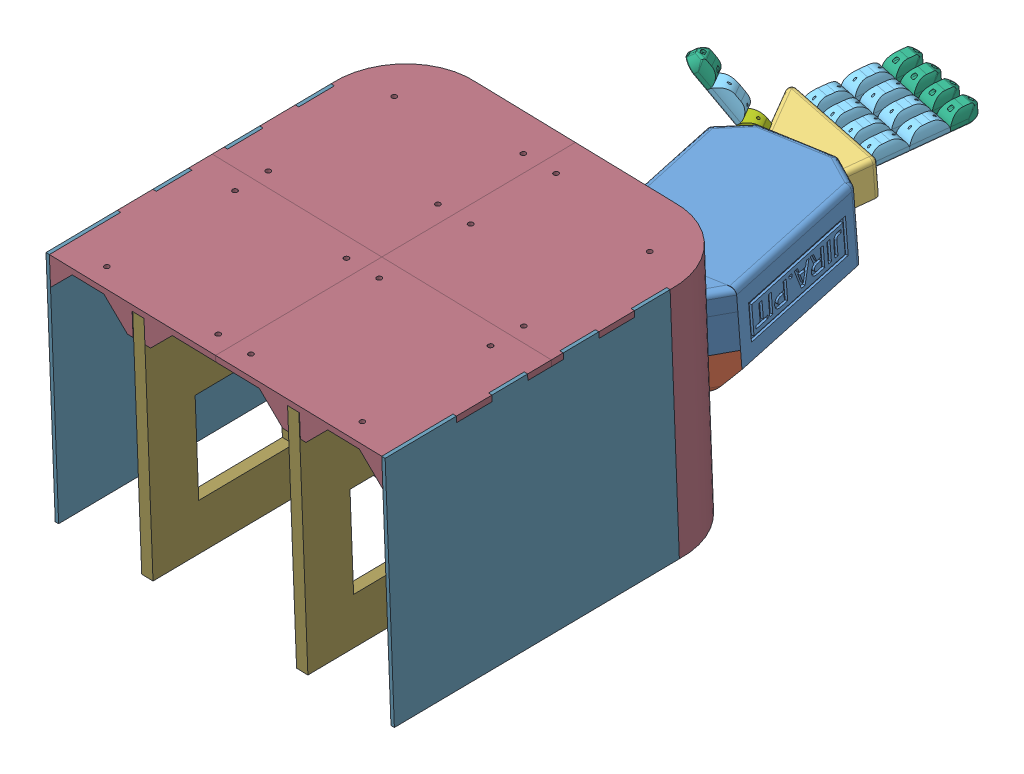
SolidWorks assembly Assem, configuration Default. Lengths in mm.
Overall size (307.81 220.18 663.52).
29 component instances, 15 part files, 77 mates.
Components (placement in the parent):
- LowerArm-1: LowerArm [Default] at (-155.348 -1.3022 43.2847) x (-0.988027 -0.013839 0.153662) z (0.154272 -0.076158 0.985089) size (110 63 197.6)
- LowerArmJoint-1: LowerArmJoint [Default] at (-124.2195 -72.1225 181.1445) x (0.154272 -0.076158 0.985089) z (0.988027 0.013839 -0.153662) size (64.86 30 110)
- Palm-1: Palm [Default] at (-140.1388 -9.6881 -22.7507) x (-0.988027 -0.013839 0.153662) z (0.154272 -0.076158 0.985089) size (87.73 30 62.31)
- UpperArm-1: UpperArm [Default] at (-132.8487 -39.1925 297.2691) x (-0.024858 -0.077406 0.99669) z (0.999689 0 0.024933) size (144 70 85.19)
- Finger-1: Finger [Default] at (-170.0006 -16.6103 30.209) x (0.981205 -0.013043 0.192525) z (-0.192957 -0.076299 0.978236) size (15.02 13 30)
- FingerTip-1: FingerTip [Default] at (-157.8446 -11.8036 -31.4185) x (0.981205 -0.013043 0.192525) z (-0.192957 -0.076299 0.978236) size (15.05 13 24.05)
- Finger-2: Finger [Default] at (-164.2119 -14.3213 0.8619) x (0.981205 -0.013043 0.192525) z (-0.192957 -0.076299 0.978236) size (15.02 13 30)
- Finger-3: Finger [Default] at (-183.836 -14.0604 -2.9886) x (0.981205 -0.013043 0.192525) z (-0.192957 -0.076299 0.978236) size (15.02 13 30)
- FingerTip-2: FingerTip [Default] at (-177.4687 -11.5427 -35.269) x (0.981205 -0.013043 0.192525) z (-0.192957 -0.076299 0.978236) size (15.05 13 24.05)
- Finger-4: Finger [Default] at (-189.6247 -16.3494 26.3585) x (0.981205 -0.013043 0.192525) z (-0.192957 -0.076299 0.978236) size (15.02 13 30)
- Finger-5: Finger [Default] at (-228.8729 -15.8277 18.6575) x (0.981205 -0.013043 0.192525) z (-0.192957 -0.076299 0.978236) size (15.02 13 30)
- FingerTip-3: FingerTip [Default] at (-216.7169 -11.021 -42.97) x (0.981205 -0.013043 0.192525) z (-0.192957 -0.076299 0.978236) size (15.05 13 24.05)
- Finger-6: Finger [Default] at (-223.0842 -13.5387 -10.6896) x (0.981205 -0.013043 0.192525) z (-0.192957 -0.076299 0.978236) size (15.02 13 30)
- Finger-7: Finger [Default] at (-203.4601 -13.7996 -6.8391) x (0.981205 -0.013043 0.192525) z (-0.192957 -0.076299 0.978236) size (15.02 13 30)
- FingerTip-4: FingerTip [Default] at (-197.0928 -11.2818 -39.1195) x (0.981205 -0.013043 0.192525) z (-0.192957 -0.076299 0.978236) size (15.05 13 24.05)
- Finger-8: Finger [Default] at (-209.2488 -16.0885 22.508) x (0.981205 -0.013043 0.192525) z (-0.192957 -0.076299 0.978236) size (15.02 13 30)
- ThumbBase-1: ThumbBase [Default] at (-217.1763 -20.4802 47.8342) x (-0.482893 0.066832 -0.873125) z (0.503849 -0.794295 -0.339458) size (15.31 18.85 30.98)
- Finger-10: Finger [Default] at (-201.1767 -20.6009 38.9761) x (-0.482893 0.066832 -0.873125) z (0.503849 -0.794295 -0.339458) size (15.02 13 30)
- FingerTip-5: FingerTip [Default] at (-217.803 5.6097 50.1778) x (-0.482893 0.066832 -0.873125) z (0.503849 -0.794295 -0.339458) size (15.05 13 24.05)
- ArmGear-1: ArmGear [Default] at (-110.8327 -50.9907 296.9019) x (0.024858 0.077406 -0.99669) z (0.999689 0 0.024933) size (81.99 81.94 8)
- ServoGear-1: ServoGear [Default] at (-112.4171 -43.3937 360.4297) x (0.023749 0.304466 -0.952227) z (0.999689 0 0.024933) size (49.97 49.91 8)
- ArmShaft-1: ArmShaft [Default] at (-207.8026 -50.9907 294.4835) x (0.005579 -0.974646 -0.223685) z (0.999689 0 0.024933) size (8 8 127)
- ServoShaft-1: ServoShaft [Default] at (-225.9021 -43.3937 357.5993) x (0.019414 -0.627466 -0.778402) z (0.999689 0 0.024933) size (3.8 3.8 160)
- GearWall-1: GearWall [Default] at (-73.9011 14.411 420.4279) x (-0.999689 0 -0.024933) z (-0.024915 -0.0379 0.998971) size (10 200 300)
- GearWall-2: GearWall [Default] at (-210.8585 14.411 417.0122) x (-0.999689 0 -0.024933) z (-0.024915 -0.0379 0.998971) size (10 200 300)
- Base-2: Base [Default] at (-147.4774 119.3355 422.5737) x (-0.024915 -0.0379 0.998971) z (0.999689 0 0.024933) size (303.08 205 300.16)
- SideWall-1: SideWall [Default] at (-1.1737 15.7721 452.3243) x (0.999689 0 0.024933) z (0.024915 0.0379 -0.998971) size (3 205 240)
- SideWall-2: SideWall [Default] at (-298.0814 15.7721 444.9194) x (0.999689 0 0.024933) z (0.024915 0.0379 -0.998971) size (3 205 240)
- FloatingRoof-1: FloatingRoof [Default] at (-145.1876 19.7448 330.7617) x (-0.024915 -0.0379 0.998971) z (-0.999689 0 -0.024933) size (135 3 127)
Mates (geometry in assembly coordinates):
- Coincident1: coincident aligned: plane of FingerTip-1 through (-139.2074 -24.9713 -49.3836) normal (0.00193 -0.997 -0.077382); plane of Finger-2 through (-144.9961 -27.2603 -20.0365) normal (0.00193 -0.997 -0.077382)
- Coincident2: coincident aligned: plane of Finger-1 through (-150.7848 -29.5492 9.3106) normal (0.00193 -0.997 -0.077382); plane of Finger-2 through (-144.9961 -27.2603 -20.0365) normal (0.00193 -0.997 -0.077382)
- Coincident3: coincident aligned: line of FingerTip-1 through (-137.554 -23.9165 -62.9328) axis (-0.192957 -0.076299 0.978236); line of Finger-2 through (-140.3815 -25.0346 -48.5979) axis (-0.192957 -0.076299 0.978236)
- Coincident6: coincident aligned: line of Finger-1 through (-146.1702 -27.3235 -19.2508) axis (-0.192957 -0.076299 0.978236); line of Finger-2 through (-140.3815 -25.0346 -48.5979) axis (-0.192957 -0.076299 0.978236)
- Concentric1: concentric anti-aligned: circle of LowerArm-1; circle of UpperArm-1
- Concentric2: concentric aligned: circle of LowerArm-1; circle of UpperArm-1
- Coincident8: coincident anti-aligned: plane of LowerArm-1 through (-155.3191 -16.2572 42.1239) normal (0.00193 -0.997 -0.077382); plane of UpperArm-1 through (-109.6281 -25.9683 168.3833) normal (-0.00193 0.997 0.077382)
- Coincident13: coincident anti-aligned: plane of LowerArm-1 through (-155.2322 -61.1222 38.6418) normal (-0.154272 0.076158 -0.985089); plane of Palm-1 through (-204.2363 -45.3577 47.5349) normal (0.154272 -0.076158 0.985089)
- Concentric5: concentric anti-aligned: cylinder of Finger-1 through (-152.3769 -15.8963 -20.6061) axis (-0.192957 -0.076299 0.978236) radius 0.75; cylinder of Palm-1 through (-158.7445 -18.4142 11.6757) axis (0.192957 0.076299 -0.978236) radius 0.75
- Concentric17: concentric anti-aligned: circle of LowerArm-1; circle of Palm-1
- Concentric22: concentric anti-aligned: circle of LowerArm-1; circle of Palm-1
- Concentric24: concentric anti-aligned: circle of Finger-1; circle of Palm-1
- Coincident27: coincident anti-aligned: plane of Finger-1 through (-150.7848 -29.5492 9.3106) normal (-0.192957 -0.076299 0.978236); plane of Palm-1 through (-139.4764 -42.3611 10.5419) normal (0.192957 0.076299 -0.978236)
- Coincident28: coincident anti-aligned: plane of Finger-1 through (-144.9961 -27.2603 -20.0365) normal (0.192957 0.076299 -0.978236); plane of Finger-2 through (-144.9961 -27.2603 -20.0365) normal (-0.192957 -0.076299 0.978236)
- Coincident29: coincident anti-aligned: plane of FingerTip-1 through (-139.2074 -24.9713 -49.3836) normal (-0.192957 -0.076299 0.978236); plane of Finger-2 through (-139.2074 -24.9713 -49.3836) normal (0.192957 0.076299 -0.978236)
- Coincident30: coincident aligned: line of Finger-3 through (-160.0056 -24.7737 -52.4484) axis (-0.192957 -0.076299 0.978236); line of Finger-4 through (-165.7943 -27.0626 -23.1013) axis (-0.192957 -0.076299 0.978236)
- Coincident31: coincident aligned: line of Finger-3 through (-160.0056 -24.7737 -52.4484) axis (-0.192957 -0.076299 0.978236); line of FingerTip-2 through (-157.1781 -23.6556 -66.7833) axis (-0.192957 -0.076299 0.978236)
- Coincident32: coincident aligned: plane of Finger-3 through (-164.6202 -26.9994 -23.887) normal (0.00193 -0.997 -0.077382); plane of FingerTip-2 through (-158.8315 -24.7104 -53.2341) normal (0.00193 -0.997 -0.077382)
- Coincident33: coincident aligned: plane of Finger-3 through (-164.6202 -26.9994 -23.887) normal (0.00193 -0.997 -0.077382); plane of Finger-4 through (-170.4089 -29.2884 5.4601) normal (0.00193 -0.997 -0.077382)
- Coincident34: coincident anti-aligned: plane of Finger-3 through (-158.8315 -24.7104 -53.2341) normal (0.192957 0.076299 -0.978236); plane of FingerTip-2 through (-158.8315 -24.7104 -53.2341) normal (-0.192957 -0.076299 0.978236)
- Coincident35: coincident anti-aligned: plane of Finger-3 through (-164.6202 -26.9994 -23.887) normal (-0.192957 -0.076299 0.978236); plane of Finger-4 through (-164.6202 -26.9994 -23.887) normal (0.192957 0.076299 -0.978236)
- Coincident36: coincident aligned: line of FingerTip-3 through (-196.4263 -23.1339 -74.4843) axis (-0.192957 -0.076299 0.978236); line of Finger-6 through (-199.2538 -24.252 -60.1494) axis (-0.192957 -0.076299 0.978236)
- Coincident37: coincident aligned: plane of Finger-5 through (-209.6571 -28.7666 -2.2409) normal (0.00193 -0.997 -0.077382); plane of Finger-6 through (-203.8684 -26.4777 -31.588) normal (0.00193 -0.997 -0.077382)
- Coincident38: coincident aligned: plane of FingerTip-3 through (-198.0797 -24.1887 -60.9351) normal (0.00193 -0.997 -0.077382); plane of Finger-6 through (-203.8684 -26.4777 -31.588) normal (0.00193 -0.997 -0.077382)
- Coincident39: coincident anti-aligned: plane of FingerTip-3 through (-198.0797 -24.1887 -60.9351) normal (-0.192957 -0.076299 0.978236); plane of Finger-6 through (-198.0797 -24.1887 -60.9351) normal (0.192957 0.076299 -0.978236)
- Coincident40: coincident anti-aligned: plane of Finger-5 through (-203.8684 -26.4777 -31.588) normal (0.192957 0.076299 -0.978236); plane of Finger-6 through (-203.8684 -26.4777 -31.588) normal (-0.192957 -0.076299 0.978236)
- Coincident41: coincident aligned: line of Finger-5 through (-205.0425 -26.5409 -30.8023) axis (-0.192957 -0.076299 0.978236); line of Finger-6 through (-199.2538 -24.252 -60.1494) axis (-0.192957 -0.076299 0.978236)
- Coincident42: coincident aligned: plane of Finger-7 through (-184.2443 -26.7385 -27.7375) normal (0.00193 -0.997 -0.077382); plane of FingerTip-4 through (-178.4556 -24.4496 -57.0846) normal (0.00193 -0.997 -0.077382)
- Coincident43: coincident aligned: plane of Finger-7 through (-184.2443 -26.7385 -27.7375) normal (0.00193 -0.997 -0.077382); plane of Finger-8 through (-190.033 -29.0275 1.6096) normal (0.00193 -0.997 -0.077382)
- Coincident44: coincident aligned: line of Finger-7 through (-179.6297 -24.5128 -56.2989) axis (-0.192957 -0.076299 0.978236); line of FingerTip-4 through (-176.8022 -23.3948 -70.6338) axis (-0.192957 -0.076299 0.978236)
- Coincident45: coincident aligned: line of Finger-7 through (-179.6297 -24.5128 -56.2989) axis (-0.192957 -0.076299 0.978236); line of Finger-8 through (-185.4184 -26.8018 -26.9518) axis (-0.192957 -0.076299 0.978236)
- Coincident46: coincident anti-aligned: plane of Finger-7 through (-184.2443 -26.7385 -27.7375) normal (-0.192957 -0.076299 0.978236); plane of Finger-8 through (-184.2443 -26.7385 -27.7375) normal (0.192957 0.076299 -0.978236)
- Coincident47: coincident anti-aligned: plane of Finger-7 through (-178.4556 -24.4496 -57.0846) normal (0.192957 0.076299 -0.978236); plane of FingerTip-4 through (-178.4556 -24.4496 -57.0846) normal (-0.192957 -0.076299 0.978236)
- Coincident48: coincident anti-aligned: circle of Palm-1; circle of Finger-4
- Concentric25: concentric anti-aligned: circle of Palm-1; cylinder of Finger-4 through (-172.001 -15.6355 -24.4566) axis (-0.192957 -0.076299 0.978236) radius 0.75
- Coincident51: coincident anti-aligned: circle of Palm-1; circle of Finger-8
- Concentric29: concentric anti-aligned: circle of Palm-1; cylinder of Finger-8 through (-191.6251 -15.3746 -28.3071) axis (-0.192957 -0.076299 0.978236) radius 0.75
- Concentric30: concentric anti-aligned: circle of Palm-1; cylinder of Finger-5 through (-211.2492 -15.1137 -32.1576) axis (-0.192957 -0.076299 0.978236) radius 0.75
- Coincident54: coincident anti-aligned: circle of Palm-1; circle of Finger-5
- Coincident55: coincident anti-aligned: plane of LowerArm-1 through (-133.6341 -71.7844 176.5542) normal (0.154272 -0.076158 0.985089); plane of LowerArmJoint-1 through (-125.1161 -86.6205 174.0732) normal (-0.154272 0.076158 -0.985089)
- Concentric35: concentric aligned: circle of LowerArmJoint-1; circle of UpperArm-1
- Coincident59: coincident anti-aligned: plane of Palm-1 through (-210.2546 -30.7376 31.5387) normal (-0.00193 0.997 0.077382); plane of ThumbBase-1 through (-210.3995 -30.7176 31.2768) normal (0.00193 -0.997 -0.077382)
- Coincident61: coincident anti-aligned: plane of Palm-1 through (-235.0693 -41.0904 -8.2147) normal (-0.875677 -0.039052 0.481315); plane of ThumbBase-1 through (-215.1928 -34.0235 28.5208) normal (0.875677 0.039052 -0.481315)
- Coincident62: coincident aligned: line of Palm-1 through (-211.3653 -30.5839 29.5305) axis (-0.875677 -0.039052 0.481315); line of ThumbBase-1 through (-211.3653 -30.5839 29.5305) axis (-0.875677 -0.039052 0.481315)
- Coincident69: coincident anti-aligned: line of ThumbBase-1 through (-225.7169 -9.9489 45.866) axis (0.482893 -0.066832 0.873125); line of Finger-10 through (-222.5556 -10.3865 51.5819) axis (-0.482893 0.066832 -0.873125)
- Coincident70: coincident anti-aligned: plane of ThumbBase-1 through (-230.4659 -9.9462 38.8108) normal (-0.503849 0.794295 0.339458); plane of Finger-10 through (-230.5153 -9.9878 38.8349) normal (0.503849 -0.794295 -0.339458)
- Coincident71: coincident anti-aligned: plane of Finger-10 through (-245.6307 13.841 49.0187) normal (-0.503849 0.794295 0.339458); plane of FingerTip-5 through (-245.6307 13.841 49.0187) normal (0.503849 -0.794295 -0.339458)
- Coincident72: coincident aligned: line of Finger-10 through (-243.4821 15.6526 47.969) axis (0.482893 -0.066832 0.873125); line of FingerTip-5 through (-243.4821 15.6526 47.969) axis (0.482893 -0.066832 0.873125)
- Coincident73: coincident aligned: line of Finger-10 through (-229.799 -9.384 38.485) axis (-0.503849 0.794295 0.339458); line of FingerTip-5 through (-244.9145 14.4449 48.6688) axis (-0.503849 0.794295 0.339458)
- Coincident75: coincident aligned: plane of ThumbBase-1 through (-223.673 -18.6735 34.3859) normal (-0.482893 0.066832 -0.873125); plane of Finger-10 through (-235.7613 0.0152 42.502) normal (-0.482893 0.066832 -0.873125)
- Coincident76: coincident anti-aligned: plane of LowerArm-1 through (-155.2612 -46.1672 39.8025) normal (0.00193 -0.997 -0.077382); plane of LowerArmJoint-1 through (-146.0522 -60.5273 225.0504) normal (-0.00193 0.997 0.077382)
- Coincident77: coincident anti-aligned: plane of UpperArm-1 through (-110.8327 -50.9907 296.9019) normal (0.999689 0 0.024933); plane of ArmGear-1 through (-110.8327 -50.9907 296.9019) normal (-0.999689 0 -0.024933)
- Concentric36: concentric aligned: circle of UpperArm-1; circle of ArmGear-1
- Parallel1: parallel aligned: plane of ArmGear-1 through (-102.8352 -50.9907 297.1014) normal (0.999689 0 0.024933); plane of ServoGear-1 through (-104.4196 -43.3937 360.6291) normal (0.999689 0 0.024933)
- Coincident79: coincident aligned: plane of ArmGear-1 through (-102.8352 -50.9907 297.1014) normal (0.999689 0 0.024933); plane of ServoGear-1 through (-104.4196 -43.3937 360.6291) normal (0.999689 0 0.024933)
- Concentric38: concentric anti-aligned: circle of ArmGear-1; circle of GearWall1-1
- Concentric40: concentric anti-aligned: circle of ServoGear-1; circle of GearWall1-1
- Parallel2: parallel aligned: line of UpperArm-1 through (-102.694 -57.699 291.4404) axis (0.00193 -0.997 -0.077382); line of ArmGear-1 through (-102.7223 -57.6601 292.573) axis (0.00193 -0.997 -0.077382)
- Concentric41: concentric anti-aligned: circle of UpperArm-1; circle of GearWall1-2
- Parallel3: parallel aligned: plane of GearWall1-1 through (-87.5407 -91.2023 566.2354) normal (0.000945 -0.999282 -0.037889); plane of GearWall1-2 through (-224.4981 -91.2023 562.8196) normal (0.000945 -0.999282 -0.037889)
- Concentric42: concentric anti-aligned: circle of GearWall1-1; circle of ArmShaft-1
- Coincident81: coincident anti-aligned: plane of GearWall1-1 through (-83.898 14.411 420.1786) normal (-0.999689 0 -0.024933); plane of ArmShaft-1 through (-80.8421 -50.9907 297.6499) normal (0.999689 0 0.024933)
- Concentric43: concentric anti-aligned: circle of GearWall1-1; circle of ServoShaft-1
- Coincident82: coincident anti-aligned: plane of GearWall1-2 through (-210.8585 14.411 417.0122) normal (0.999689 0 0.024933); plane of ArmShaft-1 through (-207.8026 -50.9907 294.4835) normal (-0.999689 0 -0.024933)
- Distance1: distance = 20 mm anti-aligned: plane of UpperArm-1 through (-187.8088 -50.9907 294.9821) normal (-0.999689 0 -0.024933); plane of GearWall1-2 through (-210.8585 14.411 417.0122) normal (0.999689 0 0.024933)
- Coincident92: coincident anti-aligned: plane of GearWall1-1 through (-87.7296 108.654 573.8131) normal (-0.000945 0.999282 0.037889); plane of Base-2 through (-147.4727 114.3391 422.3843) normal (0.000945 -0.999282 -0.037889)
- Coincident95: coincident aligned: plane of GearWall1-1 through (-87.5407 -91.2023 566.2354) normal (-0.024915 -0.0379 0.998971); plane of Base-2 through (-151.2099 108.654 572.2299) normal (-0.024915 -0.0379 0.998971)
- Coincident96: coincident anti-aligned: plane of GearWall1-1 through (-83.898 14.411 420.1786) normal (-0.999689 0 -0.024933); plane of Base-2 through (-83.9736 94.3535 423.2097) normal (0.999689 0 0.024933)
- Coincident106: coincident anti-aligned: plane of Base-2 through (-145.0414 -82.1062 324.8992) normal (-0.024915 -0.0379 0.998971); plane of SideWall-1 through (4.912 -82.1062 328.639) normal (0.024915 0.0379 -0.998971)
- Coincident107: coincident aligned: plane of Base-2 through (-147.4774 119.3355 422.5737) normal (-0.000945 0.999282 0.037889); plane of SideWall-1 through (4.7182 122.7466 336.4062) normal (-0.000945 0.999282 0.037889)
- Coincident109: coincident anti-aligned: plane of Base-2 through (-0.5184 114.3391 426.0494) normal (0.999689 0 0.024933); plane of SideWall-1 through (-1.1737 15.7721 452.3243) normal (-0.999689 0 -0.024933)
- Coincident110: coincident anti-aligned: plane of Base-2 through (-145.0414 -82.1062 324.8992) normal (-0.024915 -0.0379 0.998971); plane of SideWall-2 through (-291.9957 -82.1062 321.2341) normal (0.024915 0.0379 -0.998971)
- Coincident111: coincident anti-aligned: plane of Base-2 through (-294.427 114.3391 418.7192) normal (-0.999689 0 -0.024933); plane of SideWall-2 through (-295.0823 15.7721 444.9942) normal (0.999689 0 0.024933)
- Coincident112: coincident aligned: plane of Base-2 through (-147.4774 119.3355 422.5737) normal (-0.000945 0.999282 0.037889); plane of SideWall-2 through (-292.1894 122.7466 329.0013) normal (-0.000945 0.999282 0.037889)
- Coincident113: coincident anti-aligned: plane of Base-2 through (-146.7107 -84.6455 391.8302) normal (0.024915 0.0379 -0.998971); plane of FloatingRoof-1 through (-83.3297 20.2791 397.3917) normal (-0.024915 -0.0379 0.998971)
- Coincident114: coincident anti-aligned: plane of Base-2 through (-126.9407 20.0896 401.302) normal (-0.999689 0 -0.024933); plane of FloatingRoof-1 through (-126.8161 20.2791 396.3072) normal (0.999689 0 0.024933)
- Coincident115: coincident anti-aligned: plane of Base-2 through (-80.1655 25.0924 270.5224) normal (0.000945 -0.999282 -0.037889); plane of FloatingRoof-1 through (-145.1905 22.7426 330.8754) normal (-0.000945 0.999282 0.037889)
